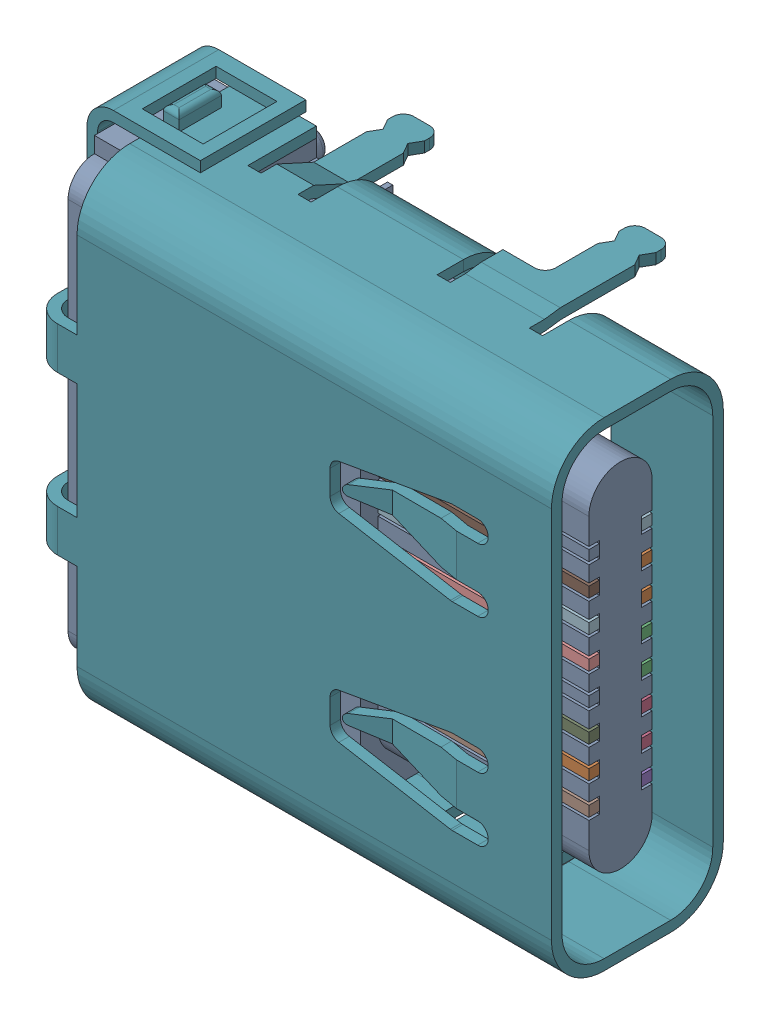
SolidWorks assembly USB2, configuration Défaut. Lengths in mm.
Overall size (9.87 9.75 4.46).
4 component instances, 1 part files, 0 mates.
Components (placement in the parent):
- KH-TYPE-C-24P-T9.87-1: KH-TYPE-C-24P-T9.87 [Défaut] at (70.797 -37.6264 -1.55) x (0 1 0) z (0 0 1) size (9.75 9.87 4.46)
  - 3D_PCB1_2021-12-30.step-1: 3D_PCB1_2021-12-30.step [Défaut] at origin size (9.75 9.87 4.46)
    - e9773ad0a1ba4615a8cdbe787346df90.step-1: e9773ad0a1ba4615a8cdbe787346df90.step [Défaut] at (5.0419 -6.8961 1.6) size (9.75 9.87 4.46)
      - COMPOUND.step_810-1: COMPOUND.step_810 [Défaut] at origin size (9.75 9.87 4.46)
